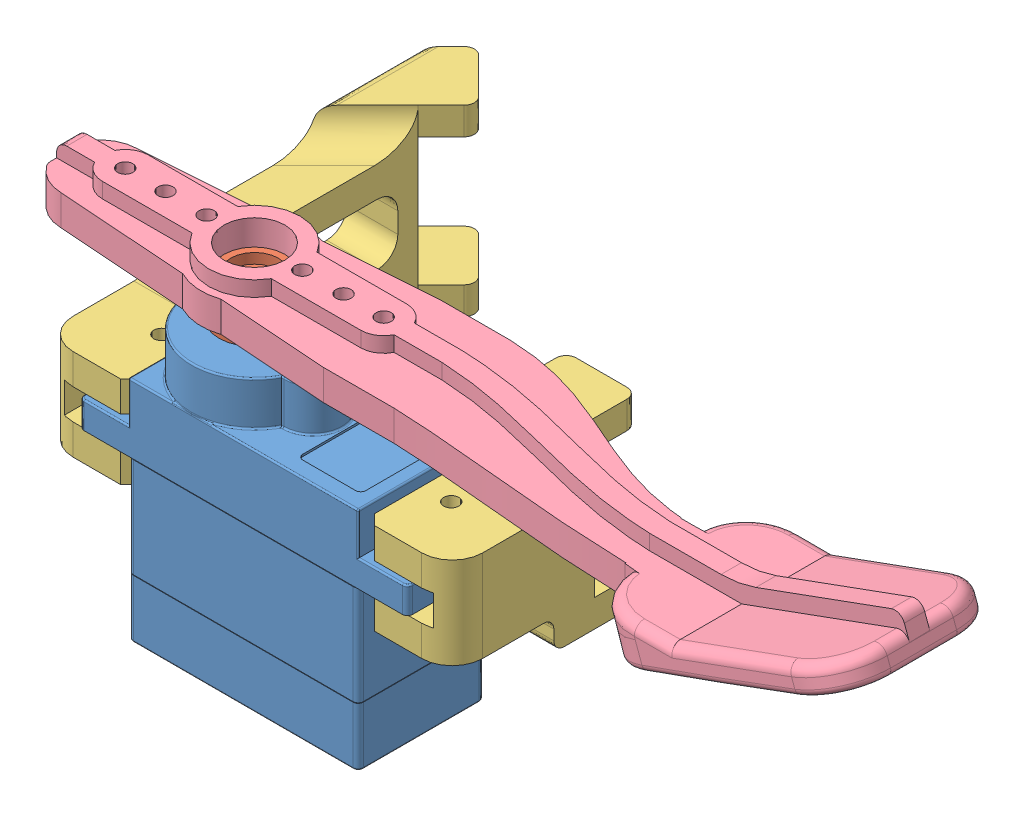
SolidWorks assembly opener, configuration Default. Lengths in mm.
Overall size (88.8 39.31 46.4).
5 component instances, 4 part files, 8 mates.
Components (placement in the parent):
- microservoAssembly-1: microservoAssembly [Default] at origin size (38.45 31.3 12.5)
  - microservoSG90-1: microservoSG90 [Default] at (7.8094 3.3655 26.0766) size (32.3 29.8 12.5)
  - microservoArm-1: microservoArm [A2] at (2.7094 34.6655 26.0766) x (-1 0 0.000751) z (0.000751 0 1) size (34.4 3.9 7)
- Part5^opener-1: Part5^opener [Default] at (66.4094 21.7655 17.8766) x (-1 0 0) z (0 0 1) size (40.3 18 39.51) (virtual)
- Part6^opener-1: Part6^opener [Default] at (2.7094 34.6655 26.0766) x (1 0 -0.000751) z (0 1 0) size (88.79 18.43 12.34) (virtual)
Mates (geometry in assembly coordinates):
- InPlace1: in place: plane of ? through (61.4094 21.7655 17.8766) normal (0 0 1); plane of ? through (0 0 17.8766) normal (0 0 1); moOrthogonalPlaneRef_w of ? through (61.4094 21.7655 17.8766) normal (0 0 1); plane of ? through (0 0 17.8766) normal (0 1 0); plane of ? through (61.4094 21.7655 17.8766) normal (0 0 1); plane of ? through (0 0 17.8766) normal (1 0 0); plane of Part5^opener-1 through (66.4094 21.7655 17.8766) normal (0 0 1); unknown of ?
- Coincident1: coincident aligned: plane of Part5^opener-1; plane of assembly
- Coincident2: coincident aligned: plane of Part5^opener-1 through (66.4094 21.7655 17.8766) normal (0 -1 0); moOrthogonalPlaneRef_w of Part11^_COLLECTOR-1 through (66.4094 21.7655 17.8766) normal (0 -1 0)
- Coincident3: coincident anti-aligned: plane of Part5^opener-1 through (66.4094 21.7655 17.8766) normal (-1 0 0); moOrthogonalPlaneRef_w of Part11^_COLLECTOR-1 through (66.4094 21.7655 17.8766) normal (1 0 0)
- InPlace2: in place: plane of microservoAssembly-1/microservoArm-1 through (17.9094 34.6655 26.0652) normal (0 1 0); plane of ? through (0 34.6655 0) normal (0 1 0); plane of microservoAssembly-1/microservoArm-1 through (17.9094 34.6655 26.0652) normal (0 1 0); plane of ? through (0 34.6655 0) normal (0 0 -1); plane of microservoAssembly-1/microservoArm-1 through (17.9094 34.6655 26.0652) normal (0 1 0); plane of ? through (0 34.6655 0) normal (1 0 0); plane of microservoAssembly-1/microservoArm-1 through (17.9094 34.6655 26.0652) normal (0 1 0); unknown of Part6^opener-1
- Coincident4: coincident aligned: plane of microservoAssembly-1/microservoArm-1; plane of Part6^opener-1
- Coincident5: coincident aligned: moOrthogonalPlaneRef_w of microservoAssembly-1/microservoArm-1 through (2.7094 34.6655 26.0766) normal (-0.000751 0 -1); plane of Part6^opener-1 through (2.7094 34.6655 26.0766) normal (-0.000751 0 -1)
- Coincident6: coincident anti-aligned: moOrthogonalPlaneRef_w of microservoAssembly-1/microservoArm-1 through (2.7094 34.6655 26.0766) normal (-1 0 0.000751); plane of Part6^opener-1 through (2.7094 34.6655 26.0766) normal (1 0 -0.000751)
